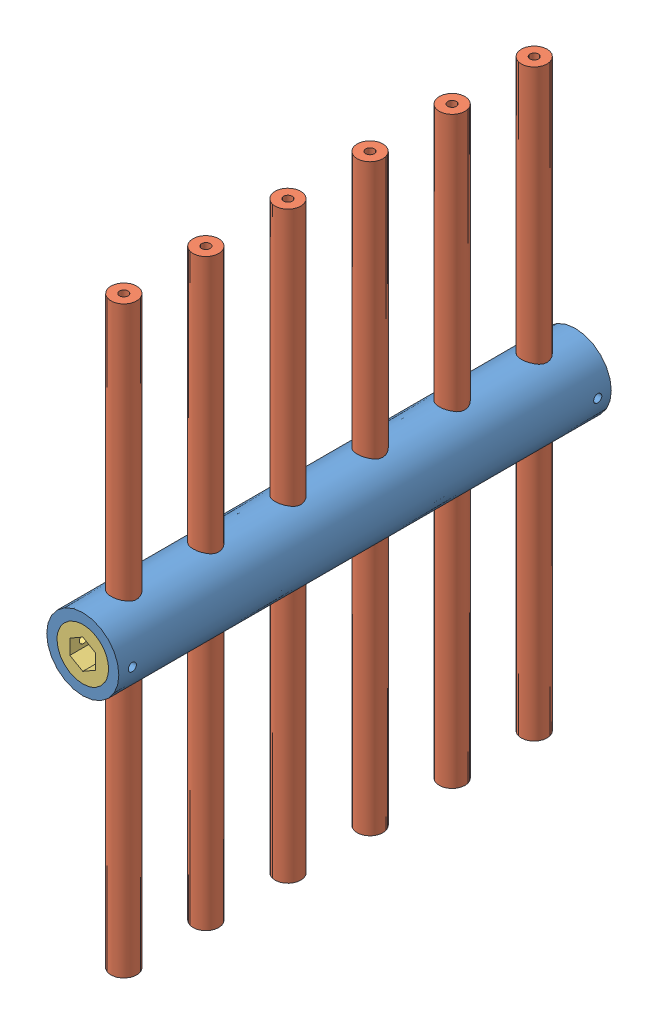
SolidWorks assembly Sweeper2, configuration Default. Lengths in mm.
Overall size (26.67 215.9 182.12).
10 component instances, 4 part files, 16 mates.
Components (placement in the parent):
- PVC2-1: PVC2 [Default] at (46.1178 93.1035 61.5834) size (26.67 26.67 182.12)
- Part5^Sweeper2-1: Part5^Sweeper2 [Default] at origin (virtual)
- Noodle-1: Noodle [Default] at (46.1178 201.0535 228.5249) x (0.990546 0 0.137182) z (0 -1 0) size (9.53 9.53 215.9)
- Noodle-2: Noodle [Default] at (46.1178 201.0535 198.1719) x (1 0 0) z (0 -1 0) size (9.53 9.53 215.9)
- Noodle-3: Noodle [Default] at (46.1178 201.0535 167.8189) x (0.97822 0 0.20757) z (0 -1 0) size (9.53 9.53 215.9)
- Noodle-4: Noodle [Default] at (46.1178 201.0535 107.1129) x (1 0 0) z (0 -1 0) size (9.53 9.53 215.9)
- Noodle-5: Noodle [Default] at (46.1178 201.0535 137.4659) x (1 0 0) z (0 -1 0) size (9.53 9.53 215.9)
- Noodle-6: Noodle [Default] at (46.1178 201.0535 76.7599) x (1 0 0) z (0 -1 0) size (9.53 9.53 215.9)
- pvcHub-1: pvcHub [Default] at (46.1178 93.1035 61.5834) x (0 1 0) z (0 0 1) size (19.05 19.05 10)
- pvcHub-2: pvcHub [Default] at (46.1178 93.1035 233.7014) x (0 1 0) z (0 0 1) size (19.05 19.05 10)
Mates (geometry in assembly coordinates):
- Concentric1: concentric: cylinder of PVC2-1 through (46.1178 106.4385 228.5249) axis (0 -1 0) radius 3.175; cylinder of Noodle-1 through (46.1178 -14.8465 228.5249) axis (0 1 0) radius 4.7625
- Concentric2: concentric: cylinder of PVC2-1 through (46.1178 106.4385 198.1719) axis (0 -1 0) radius 3.175; cylinder of Noodle-2 through (46.1178 -14.8465 198.1719) axis (0 1 0) radius 4.7625
- Concentric3: concentric: cylinder of PVC2-1 through (46.1178 106.4385 167.8189) axis (0 -1 0) radius 3.175; cylinder of Noodle-3 through (46.1178 -14.8465 167.8189) axis (0 1 0) radius 4.7625
- Concentric4: concentric: cylinder of PVC2-1 through (46.1178 106.4385 137.4659) axis (0 -1 0) radius 3.175; cylinder of Noodle-5 through (46.1178 -14.8465 137.4659) axis (0 1 0) radius 4.7625
- Concentric5: concentric: cylinder of PVC2-1 through (46.1178 106.4385 107.1129) axis (0 -1 0) radius 3.175; cylinder of Noodle-4 through (46.1178 -14.8465 107.1129) axis (0 1 0) radius 4.7625
- Concentric6: concentric: cylinder of PVC2-1 through (46.1178 106.4385 76.7599) axis (0 -1 0) radius 3.175; cylinder of Noodle-6 through (46.1178 -14.8465 76.7599) axis (0 1 0) radius 4.7625
- Coincident1: coincident: plane of Noodle-1 through (46.1178 201.0535 228.5249) normal (0 1 0); plane of Noodle-2 through (46.1178 201.0535 198.1719) normal (0 1 0)
- Coincident2: coincident: plane of Noodle-2 through (46.1178 201.0535 198.1719) normal (0 1 0); plane of Noodle-3 through (46.1178 201.0535 167.8189) normal (0 1 0)
- Coincident3: coincident: plane of Noodle-3 through (46.1178 201.0535 167.8189) normal (0 1 0); plane of Noodle-5 through (46.1178 201.0535 137.4659) normal (0 1 0)
- Coincident4: coincident: plane of Noodle-4 through (46.1178 201.0535 107.1129) normal (0 1 0); plane of Noodle-5 through (46.1178 201.0535 137.4659) normal (0 1 0)
- Coincident5: coincident: plane of Noodle-4 through (46.1178 201.0535 107.1129) normal (0 1 0); plane of Noodle-6 through (46.1178 201.0535 76.7599) normal (0 1 0)
- Distance1: distance = 107.95 mm: plane of PVC2-1 through (46.1178 93.1035 61.5834) normal (0 1 0); plane of Noodle-1 through (46.1178 201.0535 228.5249) normal (0 1 0)
- Concentric7: concentric: cylinder of PVC2-1 through (32.7828 93.1035 66.5834) axis (1 0 0) radius 1.5; cylinder of pvcHub-1 through (55.6428 93.1035 66.5834) axis (-1 0 0) radius 1.5
- Concentric8: concentric: cylinder of PVC2-1 through (46.1178 93.1035 243.7014) axis (0 0 -1) radius 9.525; cylinder of pvcHub-1 through (46.1178 93.1035 71.5834) axis (0 0 -1) radius 9.525
- Concentric9: concentric: cylinder of PVC2-1 through (32.7828 93.1035 238.7014) axis (1 0 0) radius 1.5; cylinder of pvcHub-2 through (55.6428 93.1035 238.7014) axis (-1 0 0) radius 1.5
- Concentric10: concentric: cylinder of PVC2-1 through (46.1178 93.1035 243.7014) axis (0 0 -1) radius 9.525; cylinder of pvcHub-2 through (46.1178 93.1035 243.7014) axis (0 0 -1) radius 9.525
